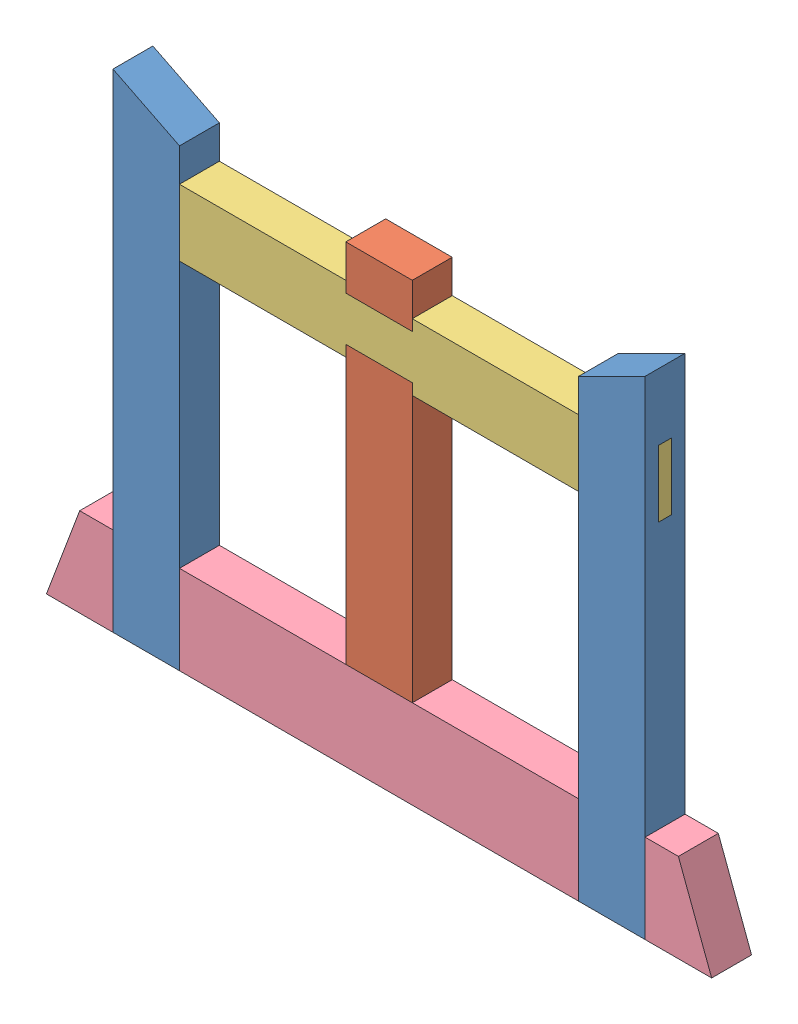
SolidWorks assembly Assem2, configuration Default. Lengths in mm.
Overall size (300 220 18).
5 component instances, 4 part files, 10 mates.
Components (placement in the parent):
- Side Rails-1: Side Rails [Default] at (21.0387 -7.4202 -6.0607) size (30 220 18)
- Middle Rail-1: Middle Rail [Default] at (-83.9613 -14.9202 -6.0607) size (30 205 18)
- Top Rail-1: Top Rail [Default] at (-83.9613 57.5798 -6.0607) x (-1 0 0) z (0 0 -1) size (240 30 18)
- Side Rails-2: Side Rails [Default] at (-188.9613 -7.4202 -6.0607) x (-1 0 0) z (0 0 -1) size (30 220 18)
- Bottom Rail-1: Bottom Rail [Default] at (-83.9613 -97.4202 -6.0607) size (300 40 18)
Mates (geometry in assembly coordinates):
- Coincident19: coincident anti-aligned: plane of Top Rail-1 through (-203.9613 42.5798 -3.0607) normal (0 0 1); plane of Side Rails-2 through (-203.9613 72.5798 -3.0607) normal (0 0 -1)
- Coincident20: coincident anti-aligned: plane of Top Rail-1 through (-173.9613 72.5798 -3.0607) normal (-1 0 0); plane of Side Rails-2 through (-173.9613 -117.4202 -15.0607) normal (1 0 0)
- Coincident21: coincident anti-aligned: plane of Top Rail-1 through (-203.9613 42.5798 -15.0607) normal (0 -1 0); plane of Side Rails-2 through (-203.9613 42.5798 -3.0607) normal (0 1 0)
- Coincident22: coincident anti-aligned: plane of Side Rails-1 through (6.0387 -77.4202 -3.0607) normal (0 -1 0); plane of Bottom Rail-1 through (66.0387 -77.4202 2.9393) normal (0 1 0)
- Coincident25: coincident anti-aligned: plane of Middle Rail-1 through (-98.9613 -77.4202 -6.0607) normal (0 0 1); plane of Bottom Rail-1 through (-68.9613 -117.4202 -6.0607) normal (0 0 -1)
- Coincident26: coincident anti-aligned: plane of Side Rails-2 through (-173.9613 -77.4202 -3.0607) normal (0 0 -1); plane of Bottom Rail-1 through (-203.9613 -117.4202 -3.0607) normal (0 0 1)
- Coincident27: coincident anti-aligned: plane of Side Rails-2 through (-203.9613 -117.4202 -15.0607) normal (-1 0 0); plane of Bottom Rail-1 through (-203.9613 -77.4202 -3.0607) normal (1 0 0)
- Coincident28: coincident anti-aligned: plane of Side Rails-1 through (6.0387 -77.4202 -9.0607) normal (0 0 1); plane of Bottom Rail-1 through (36.0387 -117.4202 -9.0607) normal (0 0 -1)
- Coincident29: coincident anti-aligned: plane of Side Rails-1 through (6.0387 -117.4202 2.9393) normal (-1 0 0); plane of Bottom Rail-1 through (6.0387 -77.4202 -3.0607) normal (1 0 0)
- Coincident30: coincident anti-aligned: plane of Middle Rail-1 through (-68.9613 -117.4202 2.9393) normal (1 0 0); plane of Top Rail-1 through (-68.9613 72.5798 -6.0607) normal (-1 0 0)
